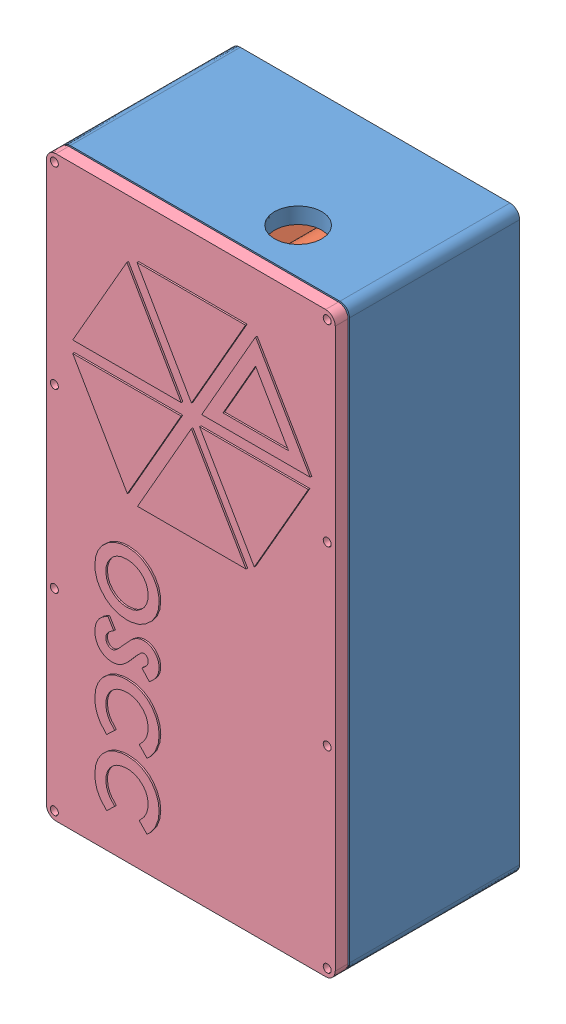
SolidWorks assembly STC_assembly, configuration Default. Lengths in mm.
Overall size (90.2 180 57.95).
7 component instances, 4 part files, 18 mates.
Components (placement in the parent):
- STC_housing-1: STC_housing [Default] at (45 -90 0) size (90 180 53)
- ArduinoUnoMockup-2: ArduinoUnoMockup [Default] at (40.3 -33.85 7) size (74.8 53.3 15.6)
- ArduinoUnoMockup-3: ArduinoUnoMockup [Default] at (40.3 -145.85 7) size (74.8 53.3 15.6)
- CANShieldMockup-1: CANShieldMockup [Default] at (40.3 -89.85 23.8957) size (74.8 53.3 15.6)
- CANShieldMockup-3: CANShieldMockup [Default] at (40.3 -89.85 36.8452) size (74.8 53.3 15.6)
- STC_lid-1: STC_lid [Default] at (45 -90 57.4453) x (0 1 0) z (0 0 -1) size (180 90 5.5)
- ArduinoUnoMockup-4: ArduinoUnoMockup [Default] at (40.3 -89.85 7) size (74.8 53.3 15.6)
Mates (geometry in assembly coordinates):
- Coincident1: coincident anti-aligned: plane of STC_housing-1 through (45 -90 0) normal (0 0 -1); plane of assembly through (0 0 0) normal (0 0 1)
- Coincident2: coincident aligned: plane of STC_housing-1 through (0 0 53) normal (0 1 0); plane of assembly through (0 0 0) normal (0 1 0)
- Coincident3: coincident anti-aligned: plane of STC_housing-1 through (0 0 53) normal (-1 0 0); plane of assembly through (0 0 0) normal (1 0 0)
- Width1: width anti-aligned: plane of STC_housing-1 through (0 -180 53) normal (0 -1 0); plane of STC_housing-1 through (0 0 53) normal (0 1 0); plane of STC_lid-1 through (90 0 53.4453) normal (0 1 0); plane of STC_lid-1 through (90 -180 53.4453) normal (0 -1 0)
- Width2: width aligned: plane of STC_housing-1 through (0 0 53) normal (-1 0 0); plane of STC_housing-1 through (90 0 53) normal (1 0 0); plane of STC_lid-1 through (90 -180 53.4453) normal (1 0 0); plane of STC_lid-1 through (0 -180 53.4453) normal (-1 0 0)
- Concentric1: concentric aligned: circle of STC_housing-1; circle of ArduinoUnoMockup-3
- Concentric2: concentric aligned: circle of STC_housing-1; circle of ArduinoUnoMockup-3
- Concentric3: concentric aligned: circle of STC_housing-1; circle of ArduinoUnoMockup-2
- Concentric4: concentric aligned: circle of STC_housing-1; circle of ArduinoUnoMockup-2
- Concentric8: concentric aligned: circle of STC_housing-1; circle of ArduinoUnoMockup-4
- Concentric9: concentric aligned: circle of STC_housing-1; circle of ArduinoUnoMockup-4
- Coincident4: coincident anti-aligned: plane of STC_housing-1 through (72.1 -81 7) normal (0 0 1); plane of ArduinoUnoMockup-4 through (40.3 -89.85 7) normal (0 0 -1)
- Coincident5: coincident anti-aligned: plane of STC_housing-1 through (72.1 -164.9 7) normal (0 0 1); plane of ArduinoUnoMockup-3 through (40.3 -145.85 7) normal (0 0 -1)
- Coincident6: coincident anti-aligned: plane of STC_housing-1 through (21.3 -9.8 7) normal (0 0 1); plane of ArduinoUnoMockup-2 through (40.3 -33.85 7) normal (0 0 -1)
- Concentric10: concentric aligned: cylinder of CANShieldMockup-1 through (72.1 -108.9 23.8957) axis (0 0 1) radius 1.75; circle of ArduinoUnoMockup-4
- Concentric11: concentric aligned: circle of CANShieldMockup-1; circle of ArduinoUnoMockup-4
- Concentric12: concentric aligned: circle of CANShieldMockup-1; circle of CANShieldMockup-3
- Concentric13: concentric aligned: circle of CANShieldMockup-1; circle of CANShieldMockup-3
